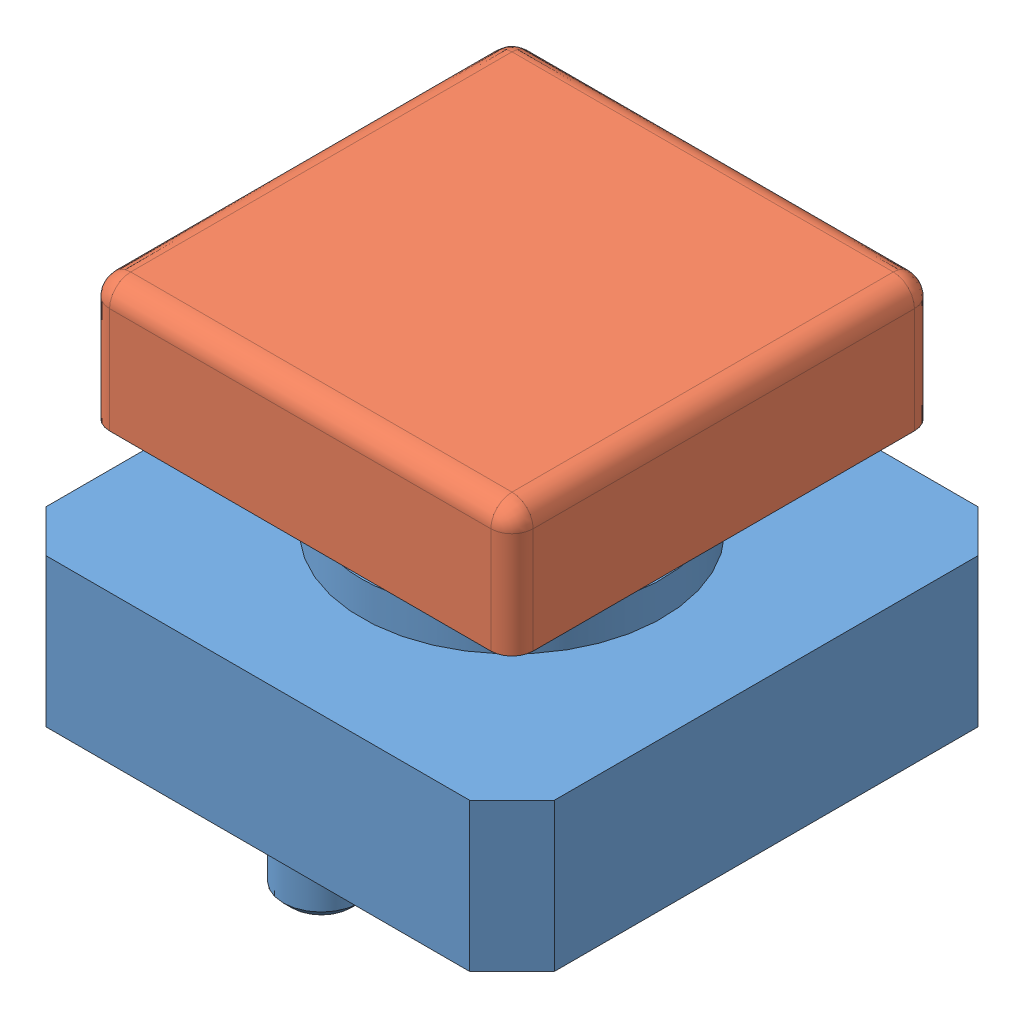
SolidWorks assembly Button Assembly, configuration Default. Lengths in mm.
Overall size (12 10.4 12).
2 component instances, 2 part files, 3 mates.
Components (placement in the parent):
- button-1: button [Default] at (-99.657 3.2054 48.4737) size (12 8.9 12)
- Cap-2: Cap [Default] at (-99.657 12.0054 48.4737) size (10 4.5 10)
Mates (geometry in assembly coordinates):
- Coincident2: coincident anti-aligned: plane of button-1 through (-99.657 7.5054 48.4737) normal (0 1 0); plane of Cap-2 through (-102.157 7.5054 51.4737) normal (0 -1 0)
- Distance1: distance = 0.3 mm anti-aligned: plane of button-1 through (-97.757 10.5054 46.5737) normal (0 0 -1); plane of Cap-2 through (-102.157 9.2941 46.2737) normal (0 0 1)
- Coincident7: coincident anti-aligned: plane of button-1 through (-97.757 10.5054 50.3737) normal (1 0 0); plane of Cap-2 through (-97.757 7.7054 49.4737) normal (-1 0 0)
